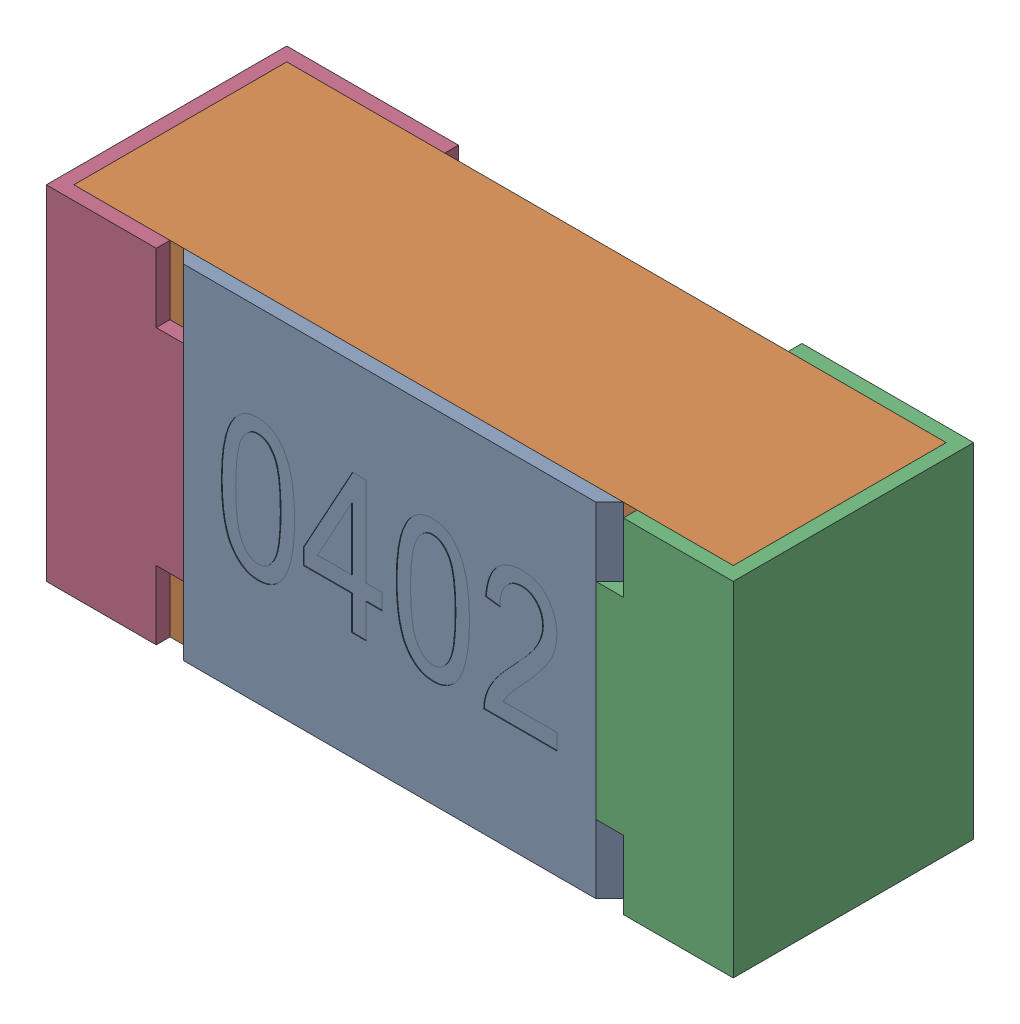
SolidWorks assembly R23, configuration Standard. Lengths in mm.
Overall size (1 0.5 0.35).
5 component instances, 4 part files, 0 mates.
Components (placement in the parent):
- R23-subassembly-1-1: R23-subassembly-1 [Standard] at (-11.6999 -17.9 0) x (1 0 0) z (0 0 1) size (1 0.5 0.35)
  - User Library-R_0402-1: User Library-R_0402 [Standard] at origin size (0.64 0.5 0.02)
  - User Library-R_0402-1-1: User Library-R_0402-1 [Standard] at origin size (0.96 0.5 0.31)
  - User Library-R_0402-2-1: User Library-R_0402-2 [Standard] at origin size (0.25 0.5 0.35)
  - User Library-R_0402-3-1: User Library-R_0402-3 [Standard] at origin size (0.25 0.5 0.35)
